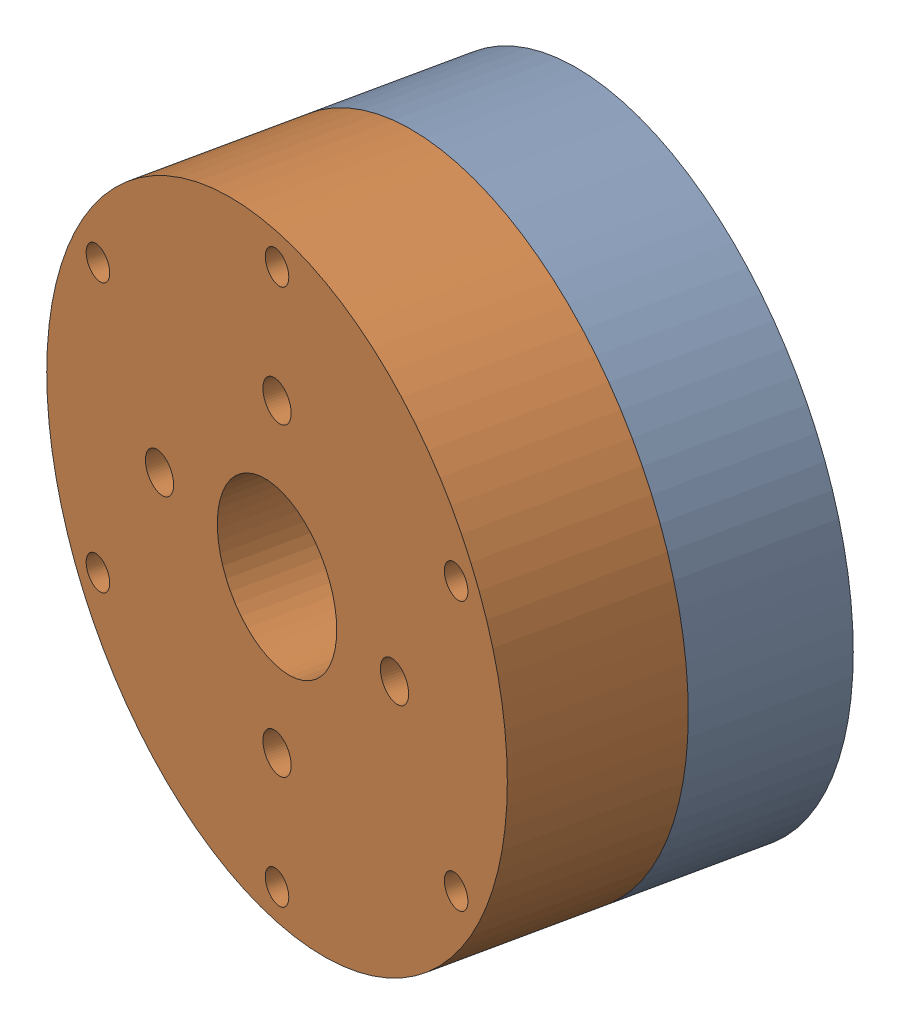
SolidWorks assembly M5005, configuration 默认. Lengths in mm.
Overall size (52.9 49 33.57).
2 component instances, 2 part files, 2 mates.
Components (placement in the parent):
- M5005下-1: M5005下 [默认] at (-40.5389 25.0298 -48.7197) x (-0.978148 0 -0.207912) z (0.207912 0 -0.978148) size (49 49 11.4)
- M5005上-2: M5005上 [默认] at (-40.5389 25.0298 -48.7197) x (0.978148 0 0.207912) z (-0.207912 0 0.978148) size (49 49 12.5)
Mates (geometry in assembly coordinates):
- 同心5: concentric anti-aligned: cylinder of M5005下-1 through (-38.1687 25.0298 -59.8706) axis (-0.207912 0 0.978148) radius 24.5; cylinder of M5005上-2 through (-48.8622 25.0298 -9.5618) axis (0.207912 0 -0.978148) radius 24.5
- 重合4: coincident anti-aligned: plane of M5005下-1 through (-40.5389 25.0298 -48.7197) normal (-0.207912 0 0.978148); plane of M5005上-2 through (-40.5389 25.0298 -48.7197) normal (0.207912 0 -0.978148)
